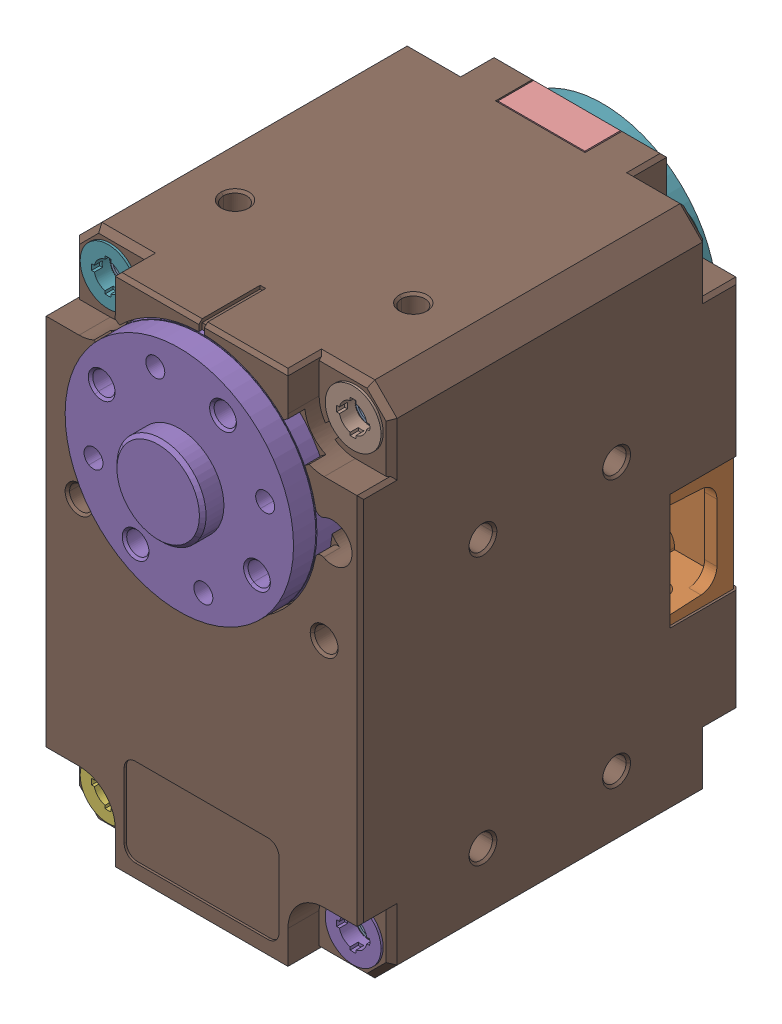
SolidWorks assembly XL-430_new_AssemsUse, configuration Default. Lengths in mm.
Overall size (28.5 49.21 40.9).
2 component instances, 2 part files, 2 mates.
Components (placement in the parent):
- XL-430_new_casepart-1: XL-430_new_casepart [Default] at (652.0872 879.6153 1273.529) size (28.5 46.5 34)
- XL-430_new_rollin2-1: XL-430_new_rollin2 [Default] at (652.0872 879.6153 1273.529) x (-0.871517 0.490365 0) z (0 0 1) size (20.5 20.5 40.9)
Mates (geometry in assembly coordinates):
- Concentric1: concentric aligned: cylinder of XL-430_new_casepart-1 through (652.0872 879.6153 1253.529) axis (0 0 1) radius 10.25; cylinder of XL-430_new_rollin2-1 through (652.0872 879.6153 1289.029) axis (0 0 1) radius 10.25
- Coincident2: coincident anti-aligned: plane of XL-430_new_casepart-1 through (652.0872 879.6153 1290.529) normal (0 0 1); circle of XL-430_new_rollin2-1
